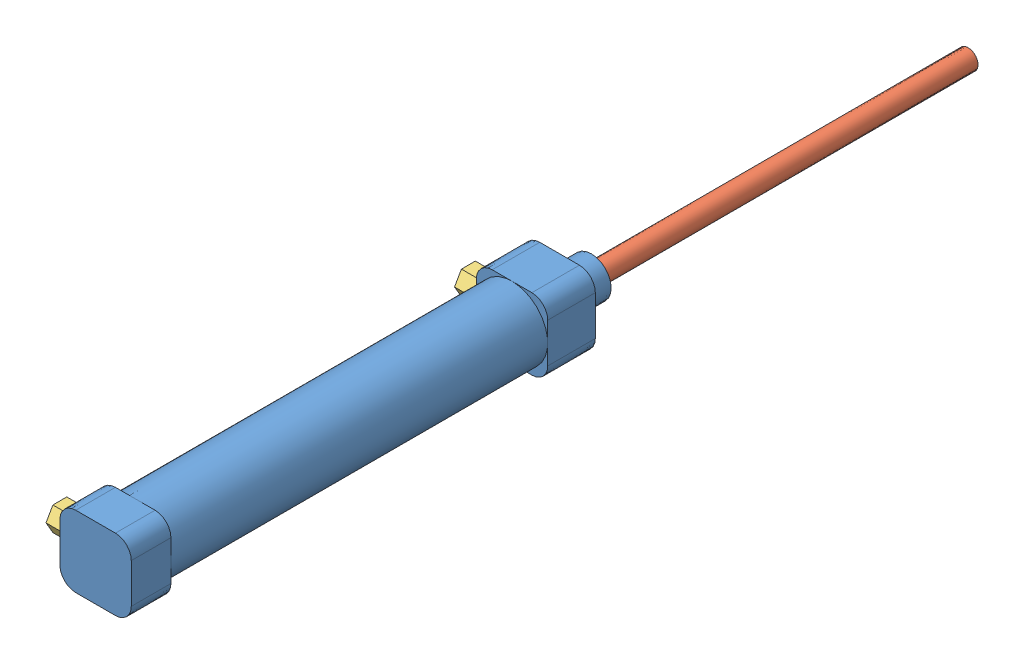
SolidWorks assembly 222.4气缸16-75装配体, configuration 默认. Lengths in mm.
Overall size (26.2 22.39 220).
4 component instances, 3 part files, 6 mates.
Components (placement in the parent):
- 222.4气缸16-75-1: 222.4气缸16-75 [默认] at (-0.3623 0.7699 82.5) size (18 18 125)
- 222.4气缸杆16-75-1: 222.4气缸杆16-75 [默认] at (-0.3623 0.7699 102.5) x (-0.598112 -0.801412 0) z (0 0 -1) size (16 16 135)
- 222.4气缸嘴16-75-1: 222.4气缸嘴16-75 [默认] at (-6.3623 0.7699 181.5) x (0 0 1) z (-1 0 0) size (7 6.07 9)
- 222.4气缸嘴16-75-2: 222.4气缸嘴16-75 [默认] at (-6.3623 0.7699 78.5) x (0 0 1) z (-1 0 0) size (7 6.07 9)
Mates (geometry in assembly coordinates):
- 同心1: concentric: cylinder of assembly; cylinder of assembly; cylinder of 222.4气缸16-75-1 through (-6.3623 0.7699 181.5) axis (-1 0 0) radius 1.9805; cylinder of 222.4气缸嘴16-75-1 through (-9.3623 0.7699 181.5) axis (1 0 0) radius 2
- 重合1: coincident: plane of assembly; plane of assembly; plane of 222.4气缸16-75-1 through (-9.3623 -4.2301 187.5) normal (-1 0 0); plane of 222.4气缸嘴16-75-1 through (-9.3623 3.7946 183.2609) normal (1 0 0)
- 同心2: concentric: cylinder of assembly; cylinder of assembly; cylinder of 222.4气缸16-75-1 through (-6.3623 0.7699 78.5) axis (-1 0 0) radius 2; cylinder of 222.4气缸嘴16-75-2 through (-9.3623 0.7699 78.5) axis (1 0 0) radius 2
- 重合2: coincident: plane of assembly; plane of assembly; plane of 222.4气缸16-75-1 through (-9.3623 -4.2301 70.5) normal (-1 0 0); plane of 222.4气缸嘴16-75-2 through (-9.3623 3.7946 80.2609) normal (1 0 0)
- 同心3: concentric: cylinder of assembly; cylinder of assembly; cylinder of 222.4气缸16-75-1 through (-0.3623 0.7699 100.5) axis (0 0 -1) radius 2.5; cylinder of 222.4气缸杆16-75-1 through (-0.3623 0.7699 -32.5) axis (0 0 1) radius 2.5
- LimitDistance1: limit distance = 103 mm: plane of assembly; plane of assembly; plane of 222.4气缸16-75-1 through (4.6377 -4.2301 70.5) normal (0 0 -1); plane of 222.4气缸杆16-75-1 through (-0.3623 0.7699 -32.5) normal (0 0 -1)
